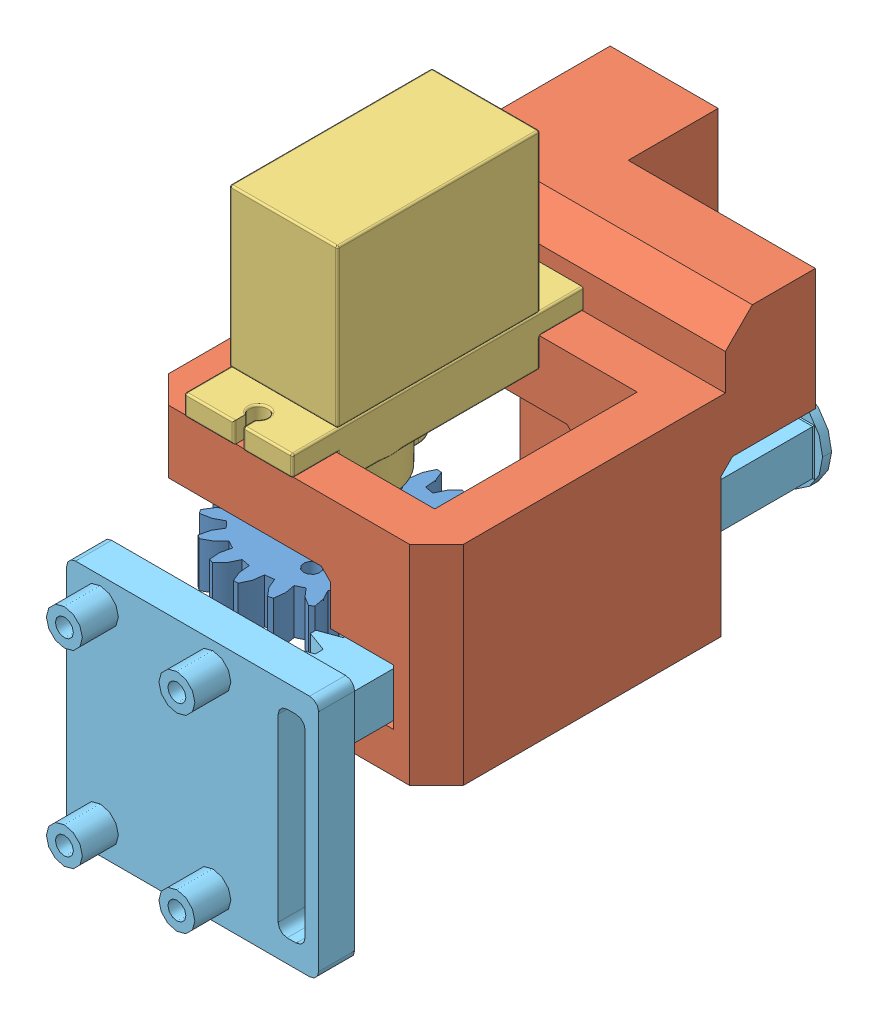
SolidWorks assembly Linear actuator assem 1, configuration Default. Lengths in mm.
Overall size (41.32 57.94 74.19).
5 component instances, 5 part files, 12 mates.
Components (placement in the parent):
- ISO - Spur gear 1M 20T 20PA 5FW ---S20A75H50L5.0N-1: ISO - Spur gear 1M 20T 20PA 5FW ---S20A75H50L5.0N [ISO - Spur gear 1M 20T 20PA 5FW ---S20A75H50L5.0N] at (-12.2719 -12.8979 27.2892) x (0 -1 0) z (0.428735 0 0.90343) size (5 21.8 21.8)
- Linear actuator servo attachment-1: Linear actuator servo attachment [Default] at (-23.2719 -6.8279 22.0392) size (32.8 45.14 52.1)
- MG90s_servo-1: MG90s_servo [Default] at (-12.2719 2.4721 22.0392) x (0 0 1) z (0 1 0) size (32.5 12 30.5)
- Servo lever-1: Servo lever [Predeterminado] at (-12.2719 -10.7479 27.2892) x (-0.428735 0 -0.90343) z (-0.90343 0 0.428735) size (12.12 4.37 7)
- ISO - Rack-spur - rectangular 1M 20PA 5FW 5PH 125L---SAll-1: ISO - Rack-spur - rectangular 1M 20PA 5FW 5PH 125L---SAll [ISO - Rack-spur - rectangular 1M 20PA 5FW 5PH 125L---SAll] at (2.5281 -17.8979 -41.3166) x (0 0 1) z (0 -1 0) size (70 28 27)
Mates (geometry in assembly coordinates):
- Concentric1: concentric: cylinder of Linear actuator servo attachment-1 through (-13.3364 3.0391 5.5979) axis (0 -1 0) radius 0.85; cylinder of MG90s_servo-1 through (-13.3364 1.2807 5.5979) axis (0 1 0) radius 1
- Coincident1: coincident: plane of Linear actuator servo attachment-1 through (-18.2719 0.1721 10.7892) normal (1 0 0); plane of MG90s_servo-1 through (-18.2719 19.9721 10.7892) normal (-1 0 0)
- Coincident2: coincident: plane of Linear actuator servo attachment-1 through (-6.2719 0.1721 10.7892) normal (0 0 1); plane of MG90s_servo-1 through (-18.2719 -3.0279 10.7892) normal (0 0 -1)
- Concentric3: concentric: cylinder of MG90s_servo-1 through (-12.2719 -10.5279 27.2892) axis (0 1 0) radius 2.275; cylinder of Servo lever-1 through (-12.2719 -11.5279 27.2892) axis (0 1 0) radius 2.175
- Distance1: distance = 1.5 mm: plane of Servo lever-1 through (-12.2719 -8.5279 27.2892) normal (0 1 0); plane of MG90s_servo-1 through (-12.2719 -7.0279 20.7892) normal (0 -1 0)
- Coincident5: coincident: plane of Linear actuator servo attachment-1 through (-23.2719 0.1721 22.0392) normal (0 1 0); plane of MG90s_servo-1 through (-12.2719 0.1721 22.0392) normal (0 -1 0)
- Concentric4: concentric: cylinder of ISO - Spur gear 1M 20T 20PA 5FW ---S20A75H50L5.0N-1 through (-12.2719 -62.898 27.2892) axis (0 1 0) radius 2.5; cylinder of Servo lever-1 through (-12.2719 -5.6779 27.2892) axis (0 -1 0) radius 1.2
- Coincident6: coincident: plane of ISO - Spur gear 1M 20T 20PA 5FW ---S20A75H50L5.0N-1 through (-12.2719 -12.8979 27.2892) normal (0 1 0); plane of Servo lever-1 through (-12.2719 -12.8979 27.2892) normal (0 -1 0)
- Concentric5: concentric: cylinder of ISO - Spur gear 1M 20T 20PA 5FW ---S20A75H50L5.0N-1 through (-14.8443 -7.8979 21.8686) axis (0 -1 0) radius 0.9; cylinder of Servo lever-1 through (-14.8443 -2.8979 21.8686) axis (0 -1 0) radius 1
- Coincident7: coincident: plane of ISO - Spur gear 1M 20T 20PA 5FW ---S20A75H50L5.0N-1 through (-12.2719 -17.8979 27.2892) normal (0 -1 0); plane of ISO - Rack-spur - rectangular 1M 20PA 5FW 5PH 125L---SAll-1 through (-3.4719 -17.8979 -41.3166) normal (0 -1 0)
- Coincident9: coincident: plane of Linear actuator servo attachment-1 through (4.5281 0.1721 33.2892) normal (-1 0 0); plane of ISO - Rack-spur - rectangular 1M 20PA 5FW 5PH 125L---SAll-1 through (4.5281 -12.8979 -41.3166) normal (1 0 0)
- Distance2: distance = 2 mm: plane of Linear actuator servo attachment-1 through (0.5275 -15.3979 0.9892) normal (0 0 1); plane of ISO - Rack-spur - rectangular 1M 20PA 5FW 5PH 125L---SAll-1 through (2.5281 -17.8979 2.9892) normal (0 0 -1)
